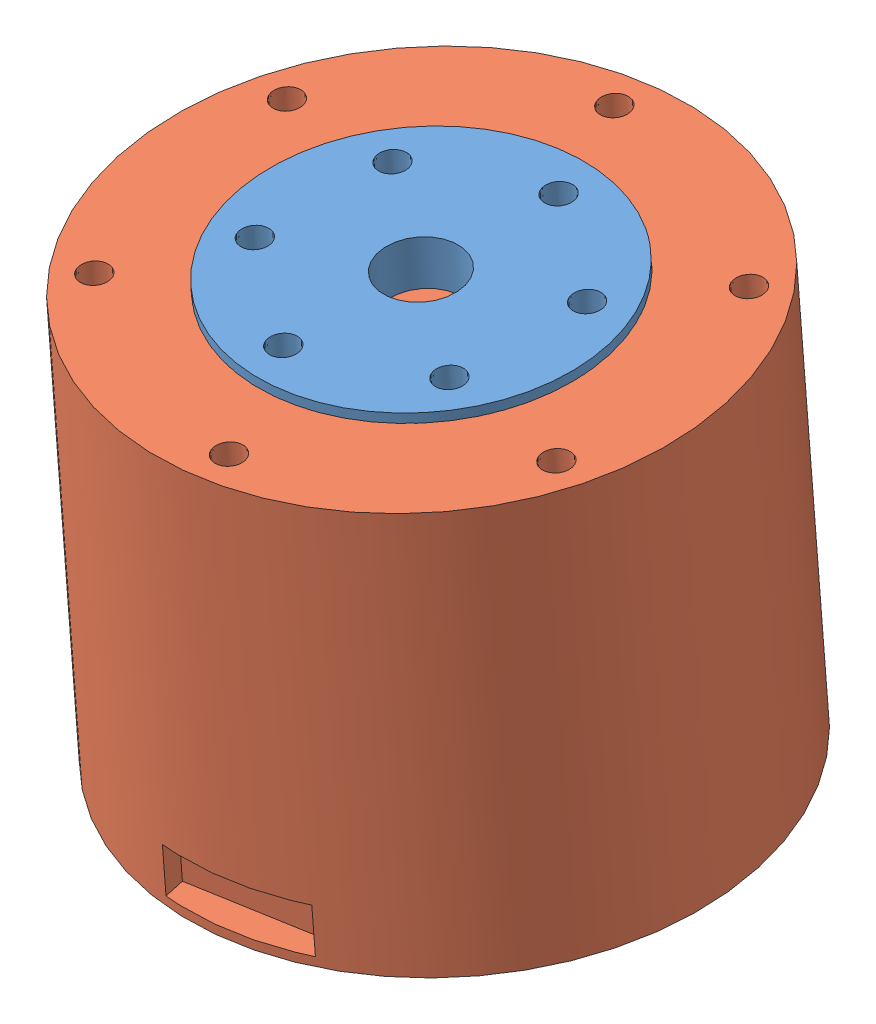
SolidWorks assembly 4310电机装配体, configuration 默认. Lengths in mm.
Overall size (65.3 50.29 68.57).
2 component instances, 2 part files, 2 mates.
Components (placement in the parent):
- 4310电机转子-1: 4310电机转子 [默认] at (-2.9158 31.0446 91.476) x (0.585967 0.063033 -0.80788) z (-0.000491 0.996998 0.077432) size (35 35 5)
- 4310电机定子-1: 4310电机定子 [默认] at (-2.8957 -9.8323 88.3013) x (0.987466 0.012704 -0.157317) z (-0.000491 0.996998 0.077432) size (57 57 45)
Mates (geometry in assembly coordinates):
- 重合1: coincident anti-aligned: plane of 电机转子-1 through (-2.9158 31.0446 91.476) normal (0.000491 -0.996998 -0.077432); plane of 电机定子-1 through (-2.9158 31.0446 91.476) normal (-0.000491 0.996998 0.077432)
- 同心1: concentric aligned: circle of 电机转子-1; circle of 电机定子-1
